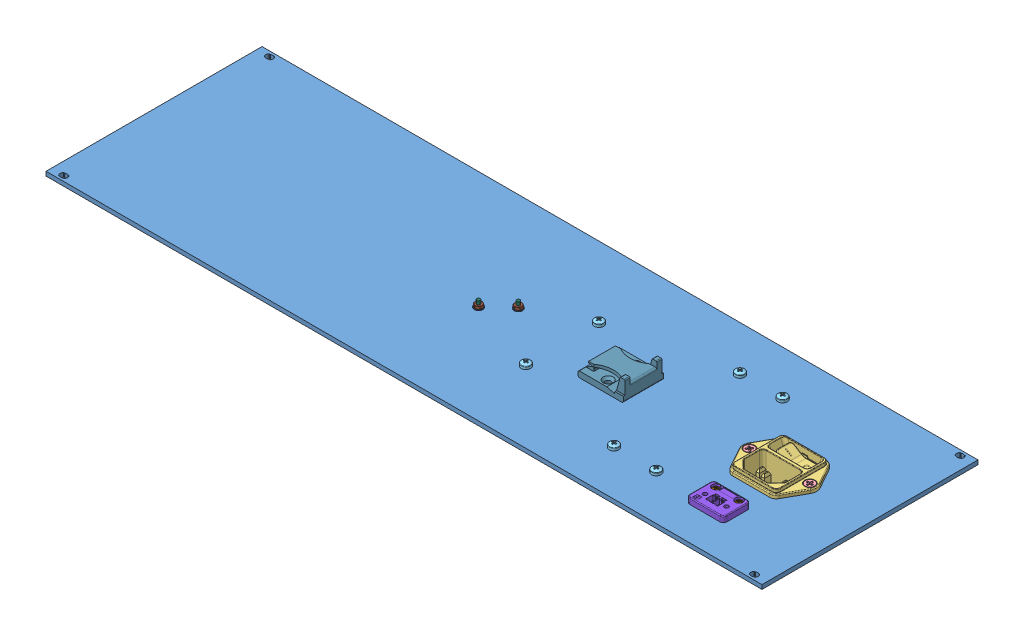
SolidWorks assembly MLA-0387-M9, configuration Default. Lengths in mm.
Overall size (426.52 43.75 128.7).
46 component instances, 18 part files, 85 mates.
Components (placement in the parent):
- MLA-0387-M8-1: MLA-0387-M8 [Default] at (14.077 -174.6299 585.4715) size (426.52 2.5 128.7)
- ECL15US12-S-1: ECL15US12-S [Default] at (340.987 202.9701 302.5215) x (0 0 -1) z (1 0 0) size (84 26.49 34.5)
- DC11_0001_001-1: DC11_0001_001 [Default] at (389.437 205.4701 308.5715) x (1 0 0) z (0 1 0) size (44 34 36.95)
- SCREW_ISO 7046-1: SCREW_ISO 7046 [VIJAK M 3x 10] at (371.437 207.6701 302.5215) x (0 -1 0) z (-0.609119 0 0.793079) size (10 5.6 5.6)
- SCREW_ISO 7046-2: SCREW_ISO 7046 [VIJAK M 3x 10] at (407.437 207.6701 302.5215) x (0 -1 0) z (0 0 1) size (10 5.6 5.6)
- M3 X 10mm Screw-1: M3 X 10mm Screw [Default] at (328.287 207.8701 340.0215) x (0 -1 0) z (0 0 1) size (12.61 5.6 5.6)
- M3 X 10mm Screw-2: M3 X 10mm Screw [Default] at (353.687 207.8701 340.2611) x (0 -1 0) z (0 0 1) size (12.61 5.6 5.6)
- M3 X 10mm Screw-3: M3 X 10mm Screw [Default] at (353.687 207.8701 265.0215) x (0 -1 0) z (0 0 1) size (12.61 5.6 5.6)
- M3 X 10mm Screw-4: M3 X 10mm Screw [Default] at (328.287 207.8701 265.0215) x (0 -1 0) z (0 0 1) size (12.61 5.6 5.6)
- M3 screw size FLAT WASHER-1: M3 screw size FLAT WASHER [Default] at (407.437 202.9701 302.5215) x (0.944963 0 -0.327176) z (0 -1 0) size (7 7 0.6)
- M3 screw size FLAT WASHER-2: M3 screw size FLAT WASHER [Default] at (371.437 202.3701 302.5215) x (1 0 0) z (0 1 0) size (7 7 0.6)
- M3 x 0.5mm Thread HEX NUT-1: M3 x 0.5mm Thread HEX NUT [Default] at (407.4348 201.1701 302.5562) x (1 0 0) z (0 1 0) size (5.5 6.35 2.6)
- M3 x 0.5mm Thread HEX NUT-2: M3 x 0.5mm Thread HEX NUT [Default] at (371.4463 201.1701 302.55) x (1 0 0) z (0 1 0) size (5.5 6.35 2.6)
- M3 screw size FLAT WASHER-3: M3 screw size FLAT WASHER [Default] at (353.687 199.8701 340.2611) x (1 0 0) z (0 1 0) size (7 7 0.6)
- M3 screw size FLAT WASHER-4: M3 screw size FLAT WASHER [Default] at (328.287 199.8701 340.0215) x (1 0 0) z (0 1 0) size (7 7 0.6)
- M3 screw size FLAT WASHER-5: M3 screw size FLAT WASHER [Default] at (328.287 200.4701 265.0215) x (1 0 0) z (0 -1 0) size (7 7 0.6)
- M3 screw size FLAT WASHER-6: M3 screw size FLAT WASHER [Default] at (353.687 200.4701 265.0215) x (1 0 0) z (0 -1 0) size (7 7 0.6)
- M3 x 0.5mm Thread HEX NUT-3: M3 x 0.5mm Thread HEX NUT [Default] at (328.3059 198.6701 265.0157) x (1 0 0) z (0 -1 0) size (5.5 6.35 2.6)
- M3 x 0.5mm Thread HEX NUT-4: M3 x 0.5mm Thread HEX NUT [Default] at (353.679 198.6701 264.9262) x (1 0 0) z (0 -1 0) size (5.5 6.35 2.6)
- M3 x 0.5mm Thread HEX NUT-5: M3 x 0.5mm Thread HEX NUT [Default] at (353.654 198.6701 340.285) x (1 0 0) z (0 1 0) size (5.5 6.35 2.6)
- M3 x 0.5mm Thread HEX NUT-6: M3 x 0.5mm Thread HEX NUT [Default] at (328.2745 198.6701 340.0301) x (1 0 0) z (0 1 0) size (5.5 6.35 2.6)
- 1829345_02-1: 1829345_02 [Default] at (387.527 203.3701 340.6215) x (0 1 0) z (-1 0 0) size (20.4 16.2 22.01)
- pan_head_phillip_mc_screw_m2-1: pan_head_phillip_mc_screw_m2 [Default] at (382.527 206.9701 333.6215) x (-0.384065 0 -0.923306) z (0.923306 0 -0.384065) size (4 9.78 4)
- pan_head_phillip_mc_screw_m2-2: pan_head_phillip_mc_screw_m2 [Default] at (396.337 206.9701 333.6215) x (0.556789 0 0.830654) z (-0.830654 0 0.556789) size (4 9.78 4)
- M2 washer-1: M2 washer [Default] at (396.337 202.6701 333.6215) size (5 0.3 5)
- M2 washer-2: M2 washer [Default] at (382.527 202.6701 333.6215) size (5 0.3 5)
- M2 Nut-1: M2 Nut [Default] at (396.337 201.0701 333.6215) x (1 0 0) z (0 -1 0) size (4 4.62 1.6)
- M2 Nut-2: M2 Nut [Default] at (382.527 201.0701 333.6215) x (1 0 0) z (0 -1 0) size (4 4.62 1.6)
- MLA-0387-C1-1: MLA-0387-C1 [Default] at (87.9984 232.5402 444.968)
- MLA-0387-C2-1: MLA-0387-C2 [Default] at (17.0703 214.5525 393.0741)
- MLA-0387-C6-1: MLA-0387-C6 [Default] at (131.9732 220.0042 408.8022)
- T9CP5A54-240-1: T9CP5A54-240 [Default] at (273.737 202.9701 327.6615) x (-1 0 0) z (0 0 1) size (27.43 27.94 50.29)
- WH5-10RJI-1: WH5-10RJI [Default] at (221.907 202.9701 302.5215) x (0 0 -1) z (-1 0 0) size (30 8.5 17)
- 060_16_QS-1: 060_16_QS [Default] at (281.287 205.4701 302.5215) x (1 0 0) z (0 1 0) size (27 24 11.5)
- M2x8 zaaggleuf-1: M2x8 zaaggleuf [Default] at (215.707 200.1701 308.1715) size (3.8 9.3 3.8)
- M2x8 zaaggleuf-2: M2x8 zaaggleuf [Default] at (228.107 200.1701 296.8715) size (3.8 9.3 3.8)
- M2 washer-3: M2 washer [Default] at (228.107 205.4701 296.8715) size (5 0.3 5)
- M2 washer-4: M2 washer [Default] at (215.707 205.4701 308.1715) size (5 0.3 5)
- M2 Nut-3: M2 Nut [Default] at (228.107 207.3701 296.8715) x (1 0 0) z (0 1 0) size (4 4.62 1.6)
- M2 Nut-4: M2 Nut [Default] at (215.707 207.3701 308.1715) x (1 0 0) z (0 1 0) size (4 4.62 1.6)
- M3 X 10mm Screw-5: M3 X 10mm Screw [Default] at (260.022 207.8701 324.2715) x (0 -1 0) z (0 0 1) size (12.61 5.6 5.6)
- M3 X 10mm Screw-6: M3 X 10mm Screw [Default] at (260.022 207.8701 280.7615) x (0 -1 0) z (0 0 1) size (12.61 5.6 5.6)
- M3 screw size FLAT WASHER-7: M3 screw size FLAT WASHER [Default] at (260.022 200.3701 280.7615) x (1 0 0) z (0 1 0) size (7 7 0.6)
- M3 screw size FLAT WASHER-8: M3 screw size FLAT WASHER [Default] at (260.022 200.3701 324.2715) x (1 0 0) z (0 1 0) size (7 7 0.6)
- M3 x 0.5mm Thread HEX NUT-7: M3 x 0.5mm Thread HEX NUT [Default] at (260.022 199.1701 280.7615) x (1 0 0) z (0 1 0) size (5.5 6.35 2.6)
- M3 x 0.5mm Thread HEX NUT-8: M3 x 0.5mm Thread HEX NUT [Default] at (260.022 199.1701 324.2715) x (1 0 0) z (0 1 0) size (5.5 6.35 2.6)
Mates (geometry in assembly coordinates):
- Coincident1: coincident anti-aligned: plane of MLA-0387-M8-1 through (22.1573 202.9701 282.3956) normal (0 -1 0); plane of ECL15US12-S-1 through (358.237 202.9701 335.5215) normal (0 1 0)
- Distance1: distance = 22.35 mm aligned: line of ECL15US12-S-1 through (324.7368 202.9701 344.5215) axis (1 0 0); plane of MLA-0387-M8-1 through (443.237 202.9701 366.8715) normal (0 0 1)
- Coincident8: coincident anti-aligned: plane of MLA-0387-M8-1 through (22.1573 205.4701 282.3956) normal (0 1 0); plane of DC11_0001_001-1 through (378.437 205.4701 289.5215) normal (0 -1 0)
- Concentric2: concentric anti-aligned: cylinder of MLA-0387-M8-1 through (371.437 212.9701 302.5215) axis (0 -1 0) radius 1.8; cylinder of DC11_0001_001-1 through (371.437 207.6701 302.5215) axis (0 1 0) radius 1.6
- Concentric3: concentric anti-aligned: cylinder of MLA-0387-M8-1 through (407.437 212.9701 302.5215) axis (0 -1 0) radius 1.8; cylinder of DC11_0001_001-1 through (407.437 207.6701 302.5215) axis (0 1 0) radius 1.6
- Distance4: distance = 85 mm: line of MLA-0387-M8-1 through (443.237 202.9701 366.8715) axis (0 0 -1); line of ECL15US12-S-1 through (358.237 202.9701 343.5217) axis (0 0 -1)
- Concentric4: concentric aligned: cone of DC11_0001_001-1 through (371.437 207.4701 302.5215) axis (0 -1 0); cone of SCREW_ISO 7046-1 through (371.437 206.1701 302.5215) axis (0 -1 0)
- Coincident9: coincident aligned: plane of DC11_0001_001-1 through (378.437 207.6701 289.5215) normal (0 1 0); plane of SCREW_ISO 7046-1 through (371.437 207.6701 302.5215) normal (0 1 0)
- Concentric5: concentric aligned: cone of DC11_0001_001-1 through (407.437 207.4701 302.5215) axis (0 -1 0); cone of SCREW_ISO 7046-2 through (407.437 206.1701 302.5215) axis (0 -1 0)
- Coincident10: coincident aligned: plane of DC11_0001_001-1 through (378.437 207.6701 289.5215) normal (0 1 0); plane of SCREW_ISO 7046-2 through (407.437 207.6701 302.5215) normal (0 1 0)
- Coincident11: coincident anti-aligned: plane of MLA-0387-M8-1 through (22.1573 205.4701 282.3956) normal (0 1 0); plane of M3 X 10mm Screw-1 through (328.287 205.4701 338.5215) normal (0 -1 0)
- Concentric6: concentric aligned: cylinder of MLA-0387-M8-1 through (328.287 212.9701 340.0215) axis (0 -1 0) radius 1.8; cylinder of M3 X 10mm Screw-1 through (328.287 195.4701 340.0215) axis (0 -1 0) radius 2.8
- Coincident12: coincident anti-aligned: plane of MLA-0387-M8-1 through (22.1573 205.4701 282.3956) normal (0 1 0); plane of M3 X 10mm Screw-2 through (353.687 205.4701 338.7611) normal (0 -1 0)
- Concentric7: concentric aligned: cylinder of MLA-0387-M8-1 through (353.687 212.9701 340.2611) axis (0 -1 0) radius 1.8; cylinder of M3 X 10mm Screw-2 through (353.687 195.4701 340.2611) axis (0 -1 0) radius 2.8
- Coincident13: coincident anti-aligned: plane of MLA-0387-M8-1 through (22.1573 205.4701 282.3956) normal (0 1 0); plane of M3 X 10mm Screw-3 through (353.687 205.4701 263.5215) normal (0 -1 0)
- Concentric8: concentric aligned: cylinder of MLA-0387-M8-1 through (353.687 212.9701 265.0215) axis (0 -1 0) radius 1.8; cylinder of M3 X 10mm Screw-3 through (353.687 195.4701 265.0215) axis (0 -1 0) radius 2.8
- Coincident14: coincident anti-aligned: plane of MLA-0387-M8-1 through (22.1573 205.4701 282.3956) normal (0 1 0); plane of M3 X 10mm Screw-4 through (328.287 205.4701 263.5215) normal (0 -1 0)
- Concentric9: concentric aligned: cylinder of MLA-0387-M8-1 through (328.287 212.9701 265.0215) axis (0 -1 0) radius 1.8; cylinder of M3 X 10mm Screw-4 through (328.287 195.4701 265.0215) axis (0 -1 0) radius 2.8
- Coincident15: coincident anti-aligned: plane of MLA-0387-M8-1 through (22.1573 202.9701 282.3956) normal (0 -1 0); plane of M3 screw size FLAT WASHER-1 through (407.437 202.9701 302.5215) normal (0 1 0)
- Concentric10: concentric anti-aligned: cylinder of M3 screw size FLAT WASHER-1 through (407.437 202.3701 302.5215) axis (0 1 0) radius 1.6; cylinder of SCREW_ISO 7046-2 through (407.437 197.6701 302.5215) axis (0 -1 0) radius 2.8
- Coincident16: coincident anti-aligned: plane of MLA-0387-M8-1 through (22.1573 202.9701 282.3956) normal (0 -1 0); plane of M3 screw size FLAT WASHER-2 through (371.437 202.9701 302.5215) normal (0 1 0)
- Concentric11: concentric aligned: cylinder of MLA-0387-M8-1 through (371.437 212.9701 302.5215) axis (0 -1 0) radius 1.8; cylinder of M3 screw size FLAT WASHER-2 through (371.437 202.9701 302.5215) axis (0 -1 0) radius 1.6
- Coincident17: coincident anti-aligned: plane of M3 screw size FLAT WASHER-1 through (407.437 202.3701 302.5215) normal (0 -1 0); plane of M3 x 0.5mm Thread HEX NUT-1 through (404.6848 202.3701 300.9685) normal (0 1 0)
- Coincident18: coincident anti-aligned: plane of M3 screw size FLAT WASHER-2 through (371.437 202.3701 302.5215) normal (0 -1 0); plane of M3 x 0.5mm Thread HEX NUT-2 through (368.6963 202.3701 300.9623) normal (0 1 0)
- Coincident19: coincident anti-aligned: plane of ECL15US12-S-1 through (358.237 200.4701 335.0215) normal (0 -1 0); plane of M3 screw size FLAT WASHER-3 through (353.687 200.4701 340.2611) normal (0 1 0)
- Concentric13: concentric aligned: cylinder of M3 X 10mm Screw-2 through (353.687 195.4701 340.2611) axis (0 -1 0) radius 2.8; cylinder of M3 screw size FLAT WASHER-3 through (353.687 200.4701 340.2611) axis (0 -1 0) radius 3.5
- Coincident20: coincident anti-aligned: plane of ECL15US12-S-1 through (358.237 200.4701 335.0215) normal (0 -1 0); plane of M3 screw size FLAT WASHER-4 through (328.287 200.4701 340.0215) normal (0 1 0)
- Concentric14: concentric aligned: cylinder of M3 X 10mm Screw-1 through (328.287 195.4701 340.0215) axis (0 -1 0) radius 2.8; cylinder of M3 screw size FLAT WASHER-4 through (328.287 200.4701 340.0215) axis (0 -1 0) radius 3.5
- Coincident21: coincident anti-aligned: plane of ECL15US12-S-1 through (358.237 200.4701 270.0215) normal (0 -1 0); plane of M3 screw size FLAT WASHER-5 through (328.287 200.4701 265.0215) normal (0 1 0)
- Concentric15: concentric aligned: cylinder of M3 X 10mm Screw-4 through (328.287 195.4701 265.0215) axis (0 -1 0) radius 2.8; circle of M3 screw size FLAT WASHER-5
- Coincident22: coincident anti-aligned: plane of ECL15US12-S-1 through (358.237 200.4701 270.0215) normal (0 -1 0); plane of M3 screw size FLAT WASHER-6 through (353.687 200.4701 265.0215) normal (0 1 0)
- Concentric16: concentric anti-aligned: circle of M3 X 10mm Screw-3; cylinder of M3 screw size FLAT WASHER-6 through (353.687 199.8701 265.0215) axis (0 1 0) radius 3.5
- Coincident24: coincident anti-aligned: plane of M3 screw size FLAT WASHER-5 through (328.287 199.8701 265.0215) normal (0 -1 0); plane of M3 x 0.5mm Thread HEX NUT-3 through (325.5559 199.8701 266.6034) normal (0 1 0)
- Coincident25: coincident anti-aligned: plane of M3 screw size FLAT WASHER-6 through (353.687 199.8701 265.0215) normal (0 -1 0); plane of M3 x 0.5mm Thread HEX NUT-4 through (350.929 199.8701 266.5139) normal (0 1 0)
- Coincident26: coincident anti-aligned: plane of M3 screw size FLAT WASHER-3 through (353.687 199.8701 340.2611) normal (0 -1 0); plane of M3 x 0.5mm Thread HEX NUT-5 through (350.904 199.8701 338.6973) normal (0 1 0)
- Coincident27: coincident anti-aligned: plane of M3 screw size FLAT WASHER-4 through (328.287 199.8701 340.0215) normal (0 -1 0); plane of M3 x 0.5mm Thread HEX NUT-6 through (325.5245 199.8701 338.4424) normal (0 1 0)
- Concentric17: concentric anti-aligned: cylinder of MLA-0387-M8-1 through (382.527 212.9701 333.6215) axis (0 -1 0) radius 1.15; cylinder of 1829345_02-1 through (382.527 196.8661 333.6215) axis (0 1 0) radius 1.15
- Concentric18: concentric anti-aligned: cylinder of MLA-0387-M8-1 through (396.337 212.9701 333.6215) axis (0 -1 0) radius 1.15; cylinder of 1829345_02-1 through (396.337 196.8661 333.6215) axis (0 1 0) radius 1.15
- Coincident32: coincident anti-aligned: plane of MLA-0387-M8-1 through (22.1573 205.4701 282.3956) normal (0 1 0); plane of 1829345_02-1 through (380.432 205.4701 348.6415) normal (0 -1 0)
- Concentric19: concentric anti-aligned: cylinder of 1829345_02-1 through (382.527 196.8661 333.6215) axis (0 1 0) radius 1.15; cylinder of pan_head_phillip_mc_screw_m2-1 through (382.527 208.7551 333.6215) axis (0 -1 0) radius 2
- Coincident33: coincident anti-aligned: plane of 1829345_02-1 through (388.0071 206.9701 335.7282) normal (0 1 0); plane of pan_head_phillip_mc_screw_m2-1 through (382.527 206.9701 333.6215) normal (0 -1 0)
- Concentric20: concentric anti-aligned: cylinder of 1829345_02-1 through (396.337 196.8661 333.6215) axis (0 1 0) radius 1.15; circle of pan_head_phillip_mc_screw_m2-2
- Coincident34: coincident anti-aligned: plane of 1829345_02-1 through (388.0071 206.9701 335.7282) normal (0 1 0); plane of pan_head_phillip_mc_screw_m2-2 through (396.337 206.9701 333.6215) normal (0 -1 0)
- Coincident35: coincident anti-aligned: plane of MLA-0387-M8-1 through (22.1573 202.9701 282.3956) normal (0 -1 0); plane of M2 washer-1 through (396.337 202.9701 333.6215) normal (0 1 0)
- Concentric22: concentric anti-aligned: cylinder of MLA-0387-M8-1 through (396.337 212.9701 333.6215) axis (0 -1 0) radius 1.15; cylinder of M2 washer-1 through (396.337 202.6701 333.6215) axis (0 1 0) radius 1.1
- Coincident36: coincident anti-aligned: plane of MLA-0387-M8-1 through (22.1573 202.9701 282.3956) normal (0 -1 0); plane of M2 washer-2 through (382.527 202.9701 333.6215) normal (0 1 0)
- Concentric23: concentric anti-aligned: cylinder of MLA-0387-M8-1 through (382.527 212.9701 333.6215) axis (0 -1 0) radius 1.15; cylinder of M2 washer-2 through (382.527 202.6701 333.6215) axis (0 1 0) radius 1.1
- Coincident37: coincident anti-aligned: plane of M2 washer-1 through (396.337 202.6701 333.6215) normal (0 -1 0); plane of M2 Nut-1 through (396.337 202.6701 335.9309) normal (0 1 0)
- Concentric25: concentric anti-aligned: circle of M2 washer-1; circle of M2 Nut-1
- Coincident38: coincident anti-aligned: plane of M2 washer-2 through (382.527 202.6701 333.6215) normal (0 -1 0); plane of M2 Nut-2 through (382.527 202.6701 335.9309) normal (0 1 0)
- Concentric26: concentric aligned: cylinder of MLA-0387-M8-1 through (382.527 212.9701 333.6215) axis (0 -1 0) radius 1.15; circle of M2 Nut-2
- Coincident39: coincident anti-aligned: plane of MLA-0387-M8-1 through (22.1573 202.9701 282.3956) normal (0 -1 0); plane of T9CP5A54-240-1 through (273.737 202.9701 327.6615) normal (0 1 0)
- Distance5: distance = 50 mm: plane of T9CP5A54-240-1 through (273.737 200.9701 327.6615) normal (1 0 0); line of ECL15US12-S-1 through (323.737 202.9701 261.5213) axis (0 0 1)
- Coincident41: coincident anti-aligned: plane of MLA-0387-M8-1 through (22.1573 202.9701 282.3956) normal (0 -1 0); plane of WH5-10RJI-1 through (221.907 202.9701 302.5215) normal (0 1 0)
- Distance6: distance = 20 mm anti-aligned: plane of WH5-10RJI-1 through (226.307 194.4701 294.0215) normal (1 0 0); plane of T9CP5A54-240-1 through (246.307 200.9701 327.6615) normal (-1 0 0)
- Distance7: distance = 39.2 mm aligned: plane of T9CP5A54-240-1 through (273.737 200.9701 277.3715) normal (0 0 -1); plane of MLA-0387-M8-1 through (16.717 202.9701 238.1715) normal (0 0 -1)
- Distance8: distance = 55.85 mm aligned: plane of WH5-10RJI-1 through (226.307 194.4701 294.0215) normal (0 0 -1); plane of MLA-0387-M8-1 through (16.717 202.9701 238.1715) normal (0 0 -1)
- Coincident45: coincident anti-aligned: plane of MLA-0387-M8-1 through (22.1573 205.4701 282.3956) normal (0 1 0); plane of 060_16_QS-1 through (294.787 205.4701 290.5215) normal (0 -1 0)
- Parallel1: parallel aligned: plane of MLA-0387-M8-1 through (443.237 202.9701 282.6215) normal (1 0 0); plane of 060_16_QS-1 through (308.287 209.5494 290.5215) normal (1 0 0)
- Distance9: distance = 20 mm: plane of 060_16_QS-1 through (308.287 209.5494 290.5215) normal (1 0 0); cylinder of M3 X 10mm Screw-1 through (328.287 195.4701 340.0215) axis (0 -1 0) radius 2.8
- Distance10: distance = 52.35 mm aligned: plane of 060_16_QS-1 through (294.8266 209.5731 290.5215) normal (0 0 -1); plane of MLA-0387-M8-1 through (16.717 202.9701 238.1715) normal (0 0 -1)
- Coincident51: coincident anti-aligned: plane of WH5-10RJI-1 through (221.907 201.4701 302.5215) normal (0 -1 0); plane of M2x8 zaaggleuf-1 through (215.707 201.4701 308.1715) normal (0 1 0)
- Concentric27: concentric anti-aligned: cylinder of WH5-10RJI-1 through (215.707 201.4701 308.1715) axis (0 1 0) radius 1.2; cylinder of M2x8 zaaggleuf-1 through (215.707 209.4701 308.1715) axis (0 -1 0) radius 1
- Coincident52: coincident anti-aligned: plane of WH5-10RJI-1 through (221.907 201.4701 302.5215) normal (0 -1 0); plane of M2x8 zaaggleuf-2 through (228.107 201.4701 296.8715) normal (0 1 0)
- Concentric28: concentric anti-aligned: circle of WH5-10RJI-1; cylinder of M2x8 zaaggleuf-2 through (228.107 209.4701 296.8715) axis (0 -1 0) radius 1
- Coincident53: coincident anti-aligned: plane of MLA-0387-M8-1 through (22.1573 205.4701 282.3956) normal (0 1 0); plane of M2 washer-3 through (228.107 205.4701 296.8715) normal (0 -1 0)
- Concentric29: concentric anti-aligned: cylinder of M2x8 zaaggleuf-2 through (228.107 209.4701 296.8715) axis (0 -1 0) radius 1; cylinder of M2 washer-3 through (228.107 205.4701 296.8715) axis (0 1 0) radius 1.1
- Coincident54: coincident anti-aligned: plane of MLA-0387-M8-1 through (22.1573 205.4701 282.3956) normal (0 1 0); plane of M2 washer-4 through (215.707 205.4701 308.1715) normal (0 -1 0)
- Concentric30: concentric anti-aligned: cylinder of M2x8 zaaggleuf-1 through (215.707 209.4701 308.1715) axis (0 -1 0) radius 1; circle of M2 washer-4
- Coincident55: coincident anti-aligned: plane of M2 washer-4 through (215.707 205.7701 308.1715) normal (0 1 0); plane of M2 Nut-4 through (215.707 205.7701 305.8621) normal (0 -1 0)
- Coincident56: coincident anti-aligned: cylinder of M2x8 zaaggleuf-1 through (215.707 209.4701 308.1715) axis (0 -1 0) radius 1; circle of M2 Nut-4
- Coincident57: coincident anti-aligned: plane of M2 washer-3 through (228.107 205.7701 296.8715) normal (0 1 0); plane of M2 Nut-3 through (228.107 205.7701 294.5621) normal (0 -1 0)
- Coincident58: coincident anti-aligned: cylinder of M2x8 zaaggleuf-2 through (228.107 209.4701 296.8715) axis (0 -1 0) radius 1; circle of M2 Nut-3
- Coincident59: coincident anti-aligned: plane of MLA-0387-M8-1 through (22.1573 205.4701 282.3956) normal (0 1 0); plane of M3 X 10mm Screw-5 through (260.022 205.4701 322.7715) normal (0 -1 0)
- Concentric31: concentric aligned: cylinder of MLA-0387-M8-1 through (260.022 212.9701 324.2715) axis (0 -1 0) radius 1.8; cylinder of M3 X 10mm Screw-5 through (260.022 195.4701 324.2715) axis (0 -1 0) radius 2.8
- Coincident60: coincident anti-aligned: plane of MLA-0387-M8-1 through (22.1573 205.4701 282.3956) normal (0 1 0); plane of M3 X 10mm Screw-6 through (260.022 205.4701 279.2615) normal (0 -1 0)
- Concentric32: concentric aligned: circle of MLA-0387-M8-1; cylinder of M3 X 10mm Screw-6 through (260.022 195.4701 280.7615) axis (0 -1 0) radius 2.8
- Coincident61: coincident anti-aligned: plane of T9CP5A54-240-1 through (273.737 200.9701 327.6615) normal (0 -1 0); plane of M3 screw size FLAT WASHER-8 through (260.022 200.9701 324.2715) normal (0 1 0)
- Concentric33: concentric aligned: cylinder of T9CP5A54-240-1 through (260.022 202.9701 324.2715) axis (0 -1 0) radius 1.8; cylinder of M3 screw size FLAT WASHER-8 through (260.022 200.9701 324.2715) axis (0 -1 0) radius 1.6
- Coincident62: coincident: plane of M3 screw size FLAT WASHER-8 through (260.022 200.3701 324.2715) normal (0 -1 0); plane of M3 x 0.5mm Thread HEX NUT-8 through (257.272 200.3701 322.6838) normal (0 1 0)
- Concentric34: concentric aligned: circle of M3 screw size FLAT WASHER-8; circle of M3 x 0.5mm Thread HEX NUT-8
- Coincident63: coincident: plane of T9CP5A54-240-1 through (273.737 200.9701 327.6615) normal (0 -1 0); plane of M3 screw size FLAT WASHER-7 through (260.022 200.9701 280.7615) normal (0 1 0)
- Concentric35: concentric aligned: cylinder of T9CP5A54-240-1 through (260.022 202.9701 280.7615) axis (0 -1 0) radius 1.8; cylinder of M3 screw size FLAT WASHER-7 through (260.022 200.9701 280.7615) axis (0 -1 0) radius 1.6
- Coincident64: coincident: plane of M3 screw size FLAT WASHER-7 through (260.022 200.3701 280.7615) normal (0 -1 0); plane of M3 x 0.5mm Thread HEX NUT-7 through (257.272 200.3701 279.1738) normal (0 1 0)
- Concentric36: concentric aligned: circle of M3 screw size FLAT WASHER-7; circle of M3 x 0.5mm Thread HEX NUT-7
